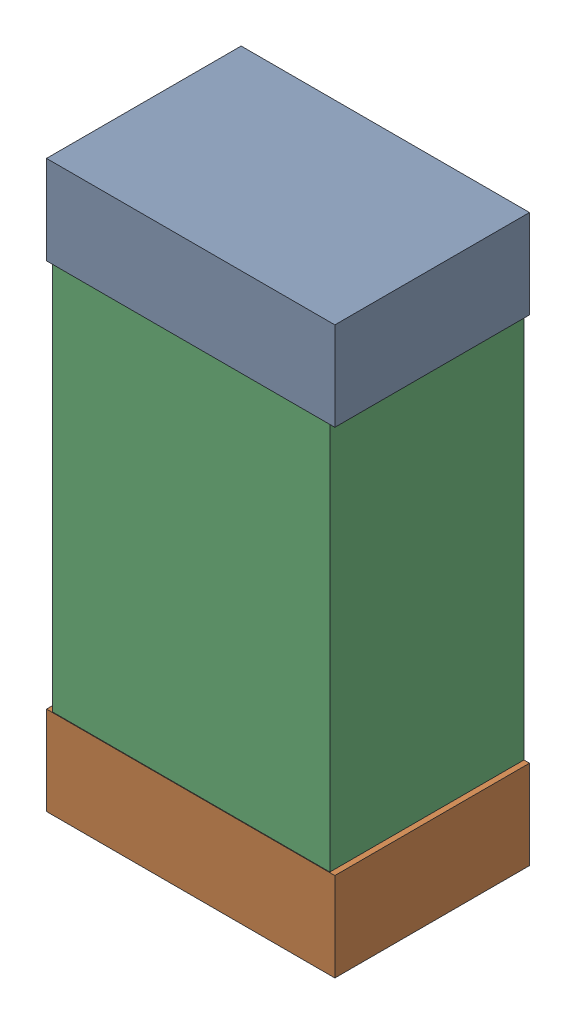
SolidWorks assembly R52, configuration Default. Lengths in mm.
Overall size (0.52 1.02 0.35).
6 component instances, 2 part files, 0 mates.
Components (placement in the parent):
- 870941120-1: 870941120 [Default] at (69.723 24.306 0) size (0.52 0.16 0.35)
  - Extruded_3-1: Extruded_3 [Default] at origin size (0.52 0.16 0.35)
- 870941120-2: 870941120 [Default] at (69.723 23.446 0) size (0.52 0.16 0.35)
  - Extruded_3-1: Extruded_3 [Default] at origin size (0.52 0.16 0.35)
- 870941280-1: 870941280 [Default] at (69.723 23.876 0) size (0.5 1 0.35)
  - Extruded_4-1: Extruded_4 [Default] at origin size (0.5 1 0.35)
